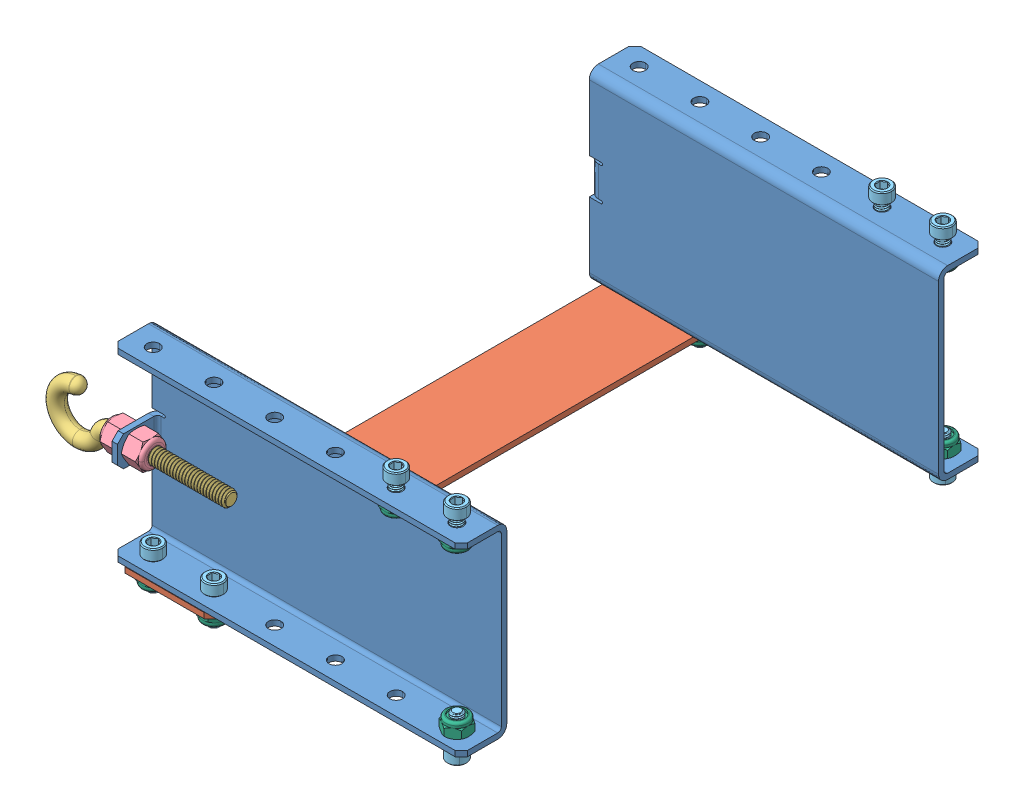
SolidWorks assembly am-2939 BatteryHolder, configuration Default. Lengths in mm.
Overall size (191.37 95.89 219.07).
27 component instances, 6 part files, 0 mates.
Components (placement in the parent):
- am-2939 BatteryHolder.STEP-1: am-2939 BatteryHolder.STEP [Default] at origin size (191.37 95.89 219.07)
  - Battery Holder.STEP-1: Battery Holder.STEP [Default] at (142.5014 92.1973 54.8206) size (146.05 77.47 19.05)
  - Battery Holder.STEP-2: Battery Holder.STEP [Default] at (142.5014 14.7273 -123.1577) x (1 0 0) z (0 0 -1) size (146.05 77.47 19.05)
  - Lower strap.STEP-1: Lower strap.STEP [Default] at (16.1214 12.4413 -34.1685) x (0 0 1) z (-1 0 0) size (219.07 2.29 38.1)
  - 14-20 Open Eye Bolt 9490T4.STEP-1: 14-20 Open Eye Bolt 9490T4.STEP [Default] at (36.1824 53.4623 67.5206) x (0 -0.999834 -0.018221) z (0 0.018221 -0.999834) size (25.34 87.6 12.15)
  - 14-20 Nylock Nut_97135A210.STEP-1: 14-20 Nylock Nut_97135A210.STEP [Default] at (-3.8176 53.4623 67.5206) x (0 -1 0) z (0 0 1) size (11.14 7.96 12.86)
  - 14-20 Nylock Nut_97135A210.STEP-2: 14-20 Nylock Nut_97135A210.STEP [Default] at (-6.1036 53.4623 67.5206) x (0 1 0) z (0 0 1) size (11.14 7.96 12.86)
  - 10-32x0500 - Mcm 91251A342_91251A342.STEP-1: 10-32x0500 - Mcm 91251A342_91251A342.STEP [Default] at (3.4214 4.3133 67.4315) x (1 0 0) z (0 -1 0) size (7.92 7.92 17.53)
  - 10-32 Nylock Nut.STEP-1: 10-32 Nylock Nut.STEP [Default] at (3.4214 12.4413 67.4315) x (0.837169 0 0.546944) z (0 -1 0) size (9.53 11.17 7.11)
  - 10-32 Nylock Nut.STEP-2: 10-32 Nylock Nut.STEP [Default] at (3.4214 12.4413 -135.7685) x (0.837169 0 0.546944) z (0 -1 0) size (9.53 11.17 7.11)
  - 10-32 Nylock Nut.STEP-3: 10-32 Nylock Nut.STEP [Default] at (28.8214 12.4413 67.4315) x (0.837169 0 0.546944) z (0 -1 0) size (9.53 11.17 7.11)
  - 10-32 Nylock Nut.STEP-4: 10-32 Nylock Nut.STEP [Default] at (28.8214 12.4413 -135.7685) x (0.837169 0 0.546944) z (0 -1 0) size (9.53 11.17 7.11)
  - 10-32x0500 - Mcm 91251A342_91251A342.STEP-2: 10-32x0500 - Mcm 91251A342_91251A342.STEP [Default] at (3.4214 4.3133 -135.7685) x (1 0 0) z (0 -1 0) size (7.92 7.92 17.53)
  - 10-32x0500 - Mcm 91251A342_91251A342.STEP-3: 10-32x0500 - Mcm 91251A342_91251A342.STEP [Default] at (28.8214 4.3133 67.4315) x (1 0 0) z (0 -1 0) size (7.92 7.92 17.53)
  - 10-32x0500 - Mcm 91251A342_91251A342.STEP-4: 10-32x0500 - Mcm 91251A342_91251A342.STEP [Default] at (28.8214 4.3133 -135.7685) x (1 0 0) z (0 -1 0) size (7.92 7.92 17.53)
  - 10-32x0500 - Mcm 91251A342_91251A342.STEP-5: 10-32x0500 - Mcm 91251A342_91251A342.STEP [Default] at (130.4214 24.2523 67.4315) x (-0.837169 0 -0.546944) z (0 1 0) size (7.92 7.92 17.53)
  - 10-32 Nylock Nut.STEP-5: 10-32 Nylock Nut.STEP [Default] at (130.4214 17.0133 67.4315) x (-1 0 0) z (0 1 0) size (9.53 11.17 7.11)
  - 10-32x0500 - Mcm 91251A342_91251A342.STEP-6: 10-32x0500 - Mcm 91251A342_91251A342.STEP [Default] at (130.4214 24.2523 -135.7685) x (-0.837169 0 -0.546944) z (0 1 0) size (7.92 7.92 17.53)
  - 10-32 Nylock Nut.STEP-6: 10-32 Nylock Nut.STEP [Default] at (130.4214 17.0133 -135.7685) x (-1 0 0) z (0 1 0) size (9.53 11.17 7.11)
  - 10-32x0500 - Mcm 91251A342_91251A342.STEP-7: 10-32x0500 - Mcm 91251A342_91251A342.STEP [Default] at (130.4214 82.6723 -135.7685) x (1 0 0) z (0 -1 0) size (7.92 7.92 17.53)
  - 10-32x0500 - Mcm 91251A342_91251A342.STEP-8: 10-32x0500 - Mcm 91251A342_91251A342.STEP [Default] at (105.0214 82.6723 -135.7685) x (1 0 0) z (0 -1 0) size (7.92 7.92 17.53)
  - 10-32x0500 - Mcm 91251A342_91251A342.STEP-9: 10-32x0500 - Mcm 91251A342_91251A342.STEP [Default] at (130.4214 82.6723 67.4315) x (1 0 0) z (0 -1 0) size (7.92 7.92 17.53)
  - 10-32x0500 - Mcm 91251A342_91251A342.STEP-10: 10-32x0500 - Mcm 91251A342_91251A342.STEP [Default] at (105.0214 82.6723 67.4315) x (1 0 0) z (0 -1 0) size (7.92 7.92 17.53)
  - 10-32 Nylock Nut.STEP-7: 10-32 Nylock Nut.STEP [Default] at (130.4214 89.9113 -135.7685) x (0.837169 0 0.546944) z (0 -1 0) size (9.53 11.17 7.11)
  - 10-32 Nylock Nut.STEP-8: 10-32 Nylock Nut.STEP [Default] at (105.0214 89.9113 -135.7685) x (0.837169 0 0.546944) z (0 -1 0) size (9.53 11.17 7.11)
  - 10-32 Nylock Nut.STEP-9: 10-32 Nylock Nut.STEP [Default] at (130.4214 89.9113 67.4315) x (0.837169 0 0.546944) z (0 -1 0) size (9.53 11.17 7.11)
  - 10-32 Nylock Nut.STEP-10: 10-32 Nylock Nut.STEP [Default] at (105.0214 89.9113 67.4315) x (0.837169 0 0.546944) z (0 -1 0) size (9.53 11.17 7.11)
